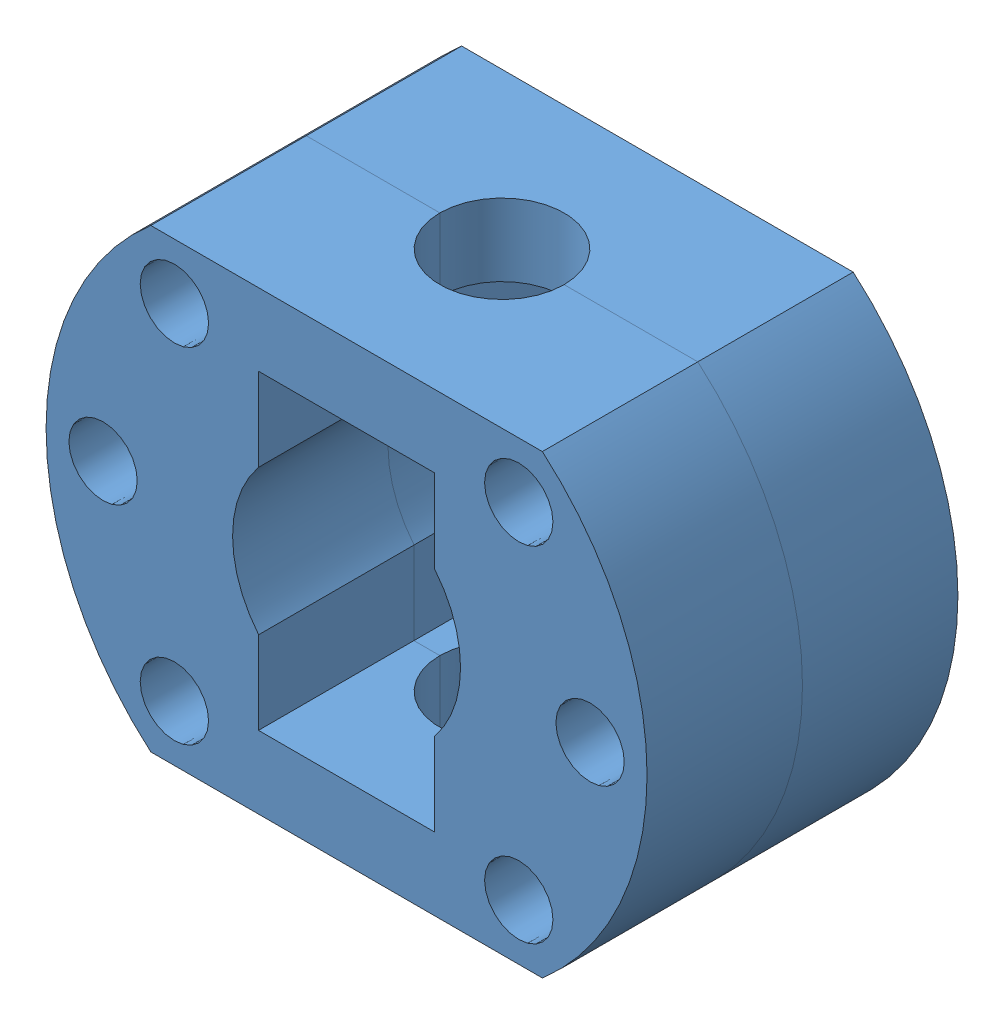
SolidWorks assembly Złożenie1, configuration Domyślna. Lengths in mm.
Overall size (58 44 30).
2 component instances, 1 part files, 3 mates.
Components (placement in the parent):
- nakladka-1: nakladka [Domyślna] at (-11.8178 4.8515 58) size (58 44 15)
- nakladka-2: nakladka [Domyślna] at (-11.8178 4.8515 73) size (58 44 15)
Mates (geometry in assembly coordinates):
- Koncentryczne1: concentric aligned: cylinder of nakladka-1 through (4.7993 21.4685 73) axis (0 0 -1) radius 3.3; cylinder of nakladka-2 through (4.7993 21.4685 88) axis (0 0 -1) radius 3.3
- Koncentryczne2: concentric aligned: cylinder of nakladka-1 through (-28.4348 -11.7655 73) axis (0 0 -1) radius 3.3; cylinder of nakladka-2 through (-28.4348 -11.7655 88) axis (0 0 -1) radius 3.3
- Wspólnie2: coincident anti-aligned: plane of nakladka-1 through (-11.8178 4.8515 73) normal (0 0 1); plane of nakladka-2 through (-11.8178 4.8515 73) normal (0 0 -1)
